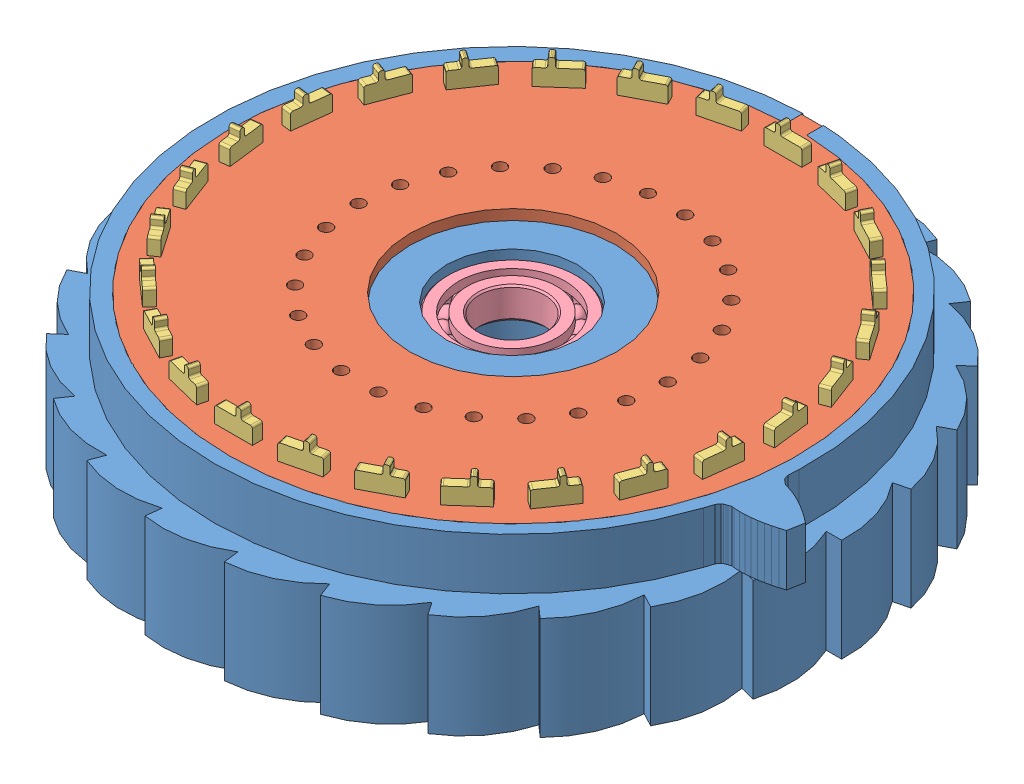
SolidWorks assembly Scrambler wheel assembly, configuration Default. Lengths in mm.
Overall size (72.54 17.5 74.67).
31 component instances, 4 part files, 7 mates.
Components (placement in the parent):
- Scrambler wheel-1: Scrambler wheel [Default] at (23.4146 24.3298 50.4806) size (65.8 15 63.85)
- PCB assembly-1: PCB assembly [Default] at (17.9086 34.8137 106.1338) x (1 0 0) z (0 1 0) size (67.78 70.24 3.5)
  - selector wheel PCB-2: selector wheel PCB [Default] at (5.7522 55.5231 3.5161) size (67.78 70.24 1)
  - spring pin-27: spring pin [Default] at (7.3927 81.0239 5.3161) x (1 0 0) z (0 -1 0) size (3.66 2.5 0.96)
  - spring pin-28: spring pin [Default] at (1.2423 80.6755 5.3161) x (0.970942 0.239316 0) z (0.239316 -0.970942 0) size (3.66 2.5 0.96)
  - spring pin-29: spring pin [Default] at (-4.6461 78.8653 5.3161) x (0.885456 0.464723 0) z (0.464723 -0.885456 0) size (3.66 2.5 0.96)
  - spring pin-30: spring pin [Default] at (-9.9301 75.6986 5.3161) x (0.748511 0.663123 0) z (0.663123 -0.748511 0) size (3.66 2.5 0.96)
  - spring pin-31: spring pin [Default] at (-14.3027 71.3593 5.3161) x (0.568065 0.822984 0) z (0.822984 -0.568065 0) size (3.66 2.5 0.96)
  - spring pin-32: spring pin [Default] at (-17.5098 66.0997 5.3161) x (0.354605 0.935016 0) z (0.935016 -0.354605 0) size (3.66 2.5 0.96)
  - spring pin-33: spring pin [Default] at (-19.365 60.2254 5.3161) x (0.120537 0.992709 0) z (0.992709 -0.120537 0) size (3.66 2.5 0.96)
  - spring pin-34: spring pin [Default] at (-19.7605 54.0778 5.3161) x (-0.120537 0.992709 0) z (0.992709 0.120537 0) size (3.66 2.5 0.96)
  - spring pin-35: spring pin [Default] at (-18.6732 48.0142 5.3161) x (-0.354605 0.935016 0) z (0.935016 0.354605 0) size (3.66 2.5 0.96)
  - spring pin-36: spring pin [Default] at (-16.1665 42.3871 5.3161) x (-0.568065 0.822984 0) z (0.822984 0.568065 0) size (3.66 2.5 0.96)
  - spring pin-37: spring pin [Default] at (-12.3859 37.5233 5.3161) x (-0.748511 0.663123 0) z (0.663123 0.748511 0) size (3.66 2.5 0.96)
  - spring pin-38: spring pin [Default] at (-7.5512 33.7056 5.3161) x (-0.885456 0.464723 0) z (0.464723 0.885456 0) size (3.66 2.5 0.96)
  - spring pin-39: spring pin [Default] at (-1.9434 31.1559 5.3161) x (-0.970942 0.239316 0) z (0.239316 0.970942 0) size (3.66 2.5 0.96)
  - spring pin-40: spring pin [Default] at (4.1117 30.0223 5.3161) x (-1 0 0) z (0 1 0) size (3.66 2.5 0.96)
  - spring pin-41: spring pin [Default] at (10.2621 30.3707 5.3161) x (-0.970942 -0.239316 0) z (-0.239316 0.970942 0) size (3.66 2.5 0.96)
  - spring pin-42: spring pin [Default] at (16.1505 32.1809 5.3161) x (-0.885456 -0.464723 0) z (-0.464723 0.885456 0) size (3.66 2.5 0.96)
  - spring pin-43: spring pin [Default] at (21.4345 35.3476 5.3161) x (-0.748511 -0.663123 0) z (-0.663123 0.748511 0) size (3.66 2.5 0.96)
  - spring pin-44: spring pin [Default] at (25.8071 39.6869 5.3161) x (-0.568065 -0.822984 0) z (-0.822984 0.568065 0) size (3.66 2.5 0.96)
  - spring pin-45: spring pin [Default] at (29.0142 44.9465 5.3161) x (-0.354605 -0.935016 0) z (-0.935016 0.354605 0) size (3.66 2.5 0.96)
  - spring pin-46: spring pin [Default] at (30.8694 50.8208 5.3161) x (-0.120537 -0.992709 0) z (-0.992709 0.120537 0) size (3.66 2.5 0.96)
  - spring pin-47: spring pin [Default] at (31.2649 56.9684 5.3161) x (0.120537 -0.992709 0) z (-0.992709 -0.120537 0) size (3.66 2.5 0.96)
  - spring pin-48: spring pin [Default] at (30.1776 63.032 5.3161) x (0.354605 -0.935016 0) z (-0.935016 -0.354605 0) size (3.66 2.5 0.96)
  - spring pin-49: spring pin [Default] at (27.6709 68.6591 5.3161) x (0.568065 -0.822984 0) z (-0.822984 -0.568065 0) size (3.66 2.5 0.96)
  - spring pin-50: spring pin [Default] at (23.8903 73.5229 5.3161) x (0.748511 -0.663123 0) z (-0.663123 -0.748511 0) size (3.66 2.5 0.96)
  - spring pin-51: spring pin [Default] at (19.0556 77.3406 5.3161) x (0.885456 -0.464723 0) z (-0.464723 -0.885456 0) size (3.66 2.5 0.96)
  - spring pin-52: spring pin [Default] at (13.4478 79.8903 5.3161) x (0.970942 -0.239316 0) z (-0.239316 -0.970942 0) size (3.66 2.5 0.96)
- selector wheel PCB-1: selector wheel PCB [Default] at (23.4146 24.3298 50.4806) x (1 0 0) z (0 1 0) size (67.78 70.24 1)
- 57155K356 ball bearing-1: 57155K356 ball bearing [57155K356] at (23.4146 35.9173 50.4806) x (1 0 0) z (0 -1 0) size (12.7 12.7 3.17)
Mates (geometry in assembly coordinates):
- Coincident1: coincident anti-aligned: plane of Scrambler wheel-1 through (23.6608 38.3298 50.6107) normal (0 1 0); plane of PCB assembly-1/selector wheel PCB-2 through (23.6608 38.3298 50.6107) normal (0 -1 0)
- Concentric1: concentric aligned: circle of PCB assembly-1/selector wheel PCB-2; circle of Scrambler wheel-1
- Coincident3: coincident anti-aligned: plane of Scrambler wheel-1 through (22.6608 38.3298 21.1289) normal (1 0 0); plane of PCB assembly-1/selector wheel PCB-2 through (22.6608 39.3298 23.1289) normal (-1 0 0)
- Coincident7: coincident anti-aligned: circle of Scrambler wheel-1; circle of selector wheel PCB-1
- Coincident8: coincident anti-aligned: plane of Scrambler wheel-1 through (24.4146 25.3298 20.9988) normal (-1 0 0); plane of selector wheel PCB-1 through (24.4146 25.3298 21.4988) normal (1 0 0)
- Concentric2: concentric anti-aligned: cylinder of Scrambler wheel-1 through (23.4146 16.3693 50.4806) axis (0 1 0) radius 6.35; cylinder of 57155K356 ball bearing-1 through (23.4146 34.3298 50.4806) axis (0 -1 0) radius 6.35
- Coincident9: coincident anti-aligned: plane of Scrambler wheel-1 through (23.4146 34.3298 50.4806) normal (0 1 0); plane of 57155K356 ball bearing-1 through (23.4146 34.3298 56.6719) normal (0 -1 0)
